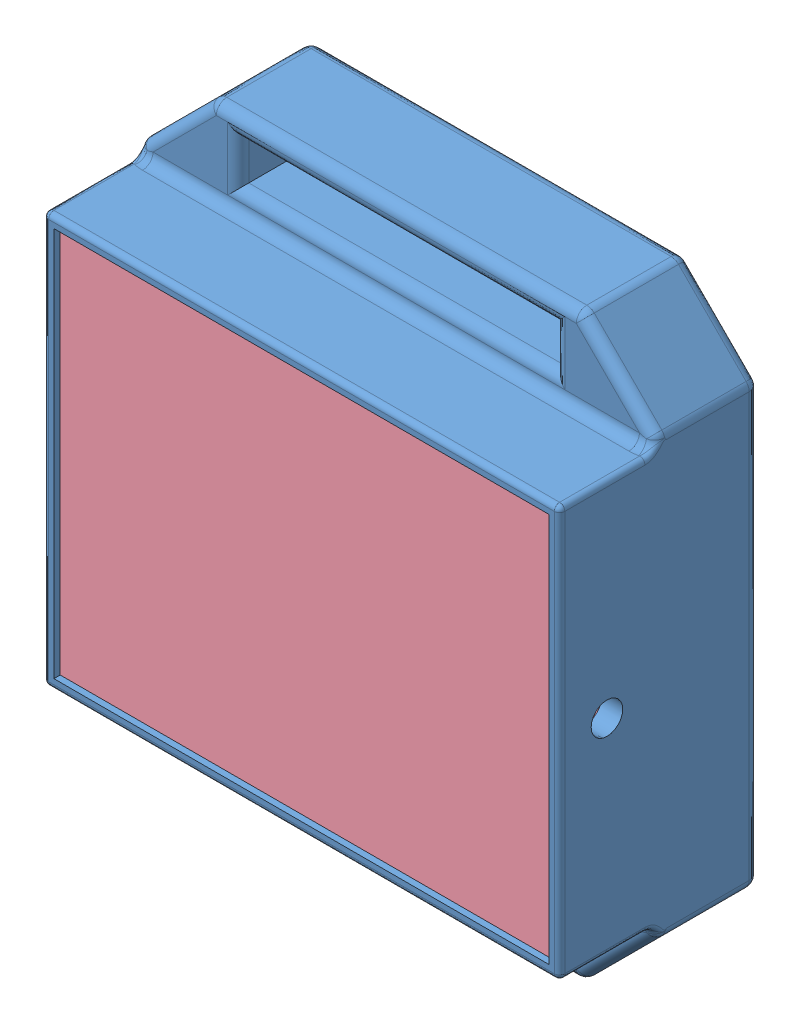
SolidWorks assembly PruebaEnsamblaje2, configuration Predeterminado. Lengths in mm.
Overall size (49.08 55 19).
4 component instances, 4 part files, 7 mates.
Components (placement in the parent):
- Gabinete-1: Gabinete [Predeterminado] at origin size (49.08 55 19)
- EnsamblajePlaca-nRF-1: EnsamblajePlaca-nRF [Predeterminado] at (-0.4636 14.9819 43.7919) x (0 1 0) z (0 0 -1) size (32 42.5 10.99)
- Bateria-1: Bateria [Default] at (8 -1.5 11.1) x (0 1 0) z (0 0 1) size (32 20 4)
- Tapa-1: Tapa [Predeterminado] at (0 0 18.5) x (0 -1 0) z (0 0 -1) size (36.8 46.8 7)
Mates (geometry in assembly coordinates):
- Coincidente1: coincident aligned: plane of Gabinete-1 through (0 0 0) normal (0 0 -1); plane of EnsamblajePlaca-nRF-1 through (-11.2024 -4.7625 0) normal (0 0 -1)
- Distancia3: distance = 1.5 mm anti-aligned: plane of EnsamblajePlaca-nRF-1 through (-16.8024 -16 9.1) normal (0 -1 0); plane of Gabinete-1 through (0 -17.5 18) normal (0 1 0)
- Distancia4: distance = 2 mm anti-aligned: plane of EnsamblajePlaca-nRF-1 through (-16.8024 -16 9.1) normal (0 0 1); plane of Bateria-1 through (8 -1.5 11.1) normal (0 0 -1)
- Distancia5: distance = 1 mm anti-aligned: plane of Bateria-1 through (18 -16.5 15.1) normal (0 -1 0); plane of Gabinete-1 through (0 -17.5 18) normal (0 1 0)
- Distancia7: distance = 4.5 mm anti-aligned: plane of Bateria-1 through (18 -16.5 15.1) normal (1 0 0); plane of Gabinete-1 through (22.5 0 18) normal (-1 0 0)
- Coincidente2: coincident aligned: circle of Gabinete-1; circle of Tapa-1
- Paralelo1: parallel anti-aligned: plane of Gabinete-1 through (0 0 18) normal (0 0 1); plane of Tapa-1 through (0 0 17.5) normal (0 0 -1)
